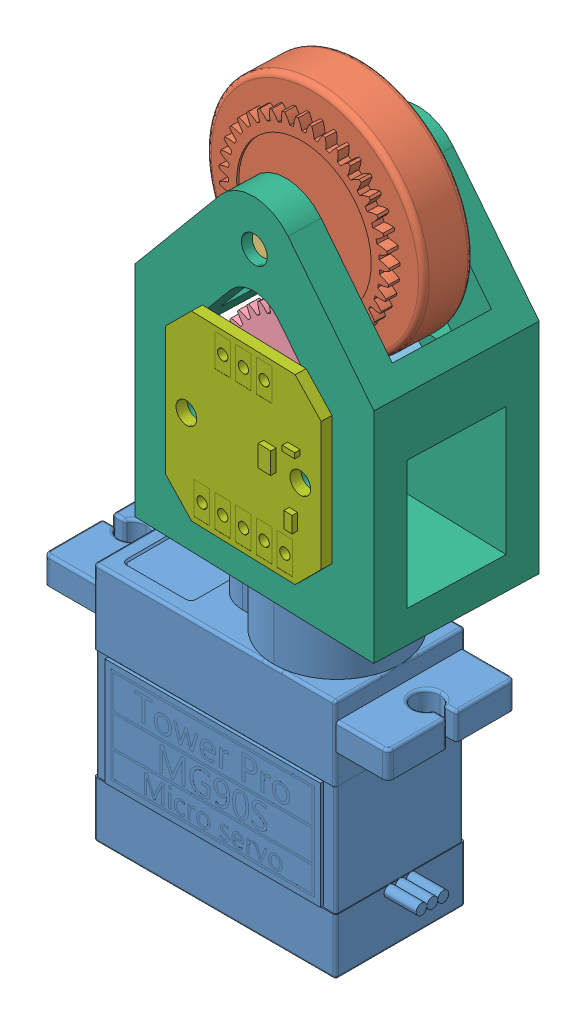
SolidWorks assembly Cum Banh, configuration Default. Lengths in mm.
Overall size (34.77 70 23.37).
9 component instances, 9 part files, 20 mates.
Components (placement in the parent):
- Tower Pro MG90S Micro servo.step-1: Tower Pro MG90S Micro servo.step [Default] at (15.3715 12.0782 26.2271) size (32.2 32.25 12.33)
- Banh xe-1: Banh xe [Default] at (25.5496 58.2792 32.0289) x (0.030859 0 -0.999524) z (-0.29972 -0.953982 -0.009253) size (8.5 21 21)
- Truc 2x14-1: Truc 2x14 [Default] at (20.7542 57.6422 25.9772) x (0.896654 -0.441865 0.027683) z (-0.030859 0 0.999524) size (2 2 14)
- Banh rang doi-1: Banh rang doi [Default] at (20.6271 42.0017 27.2888) x (0.030859 0 -0.999524) z (0.999258 0.023056 0.030851) size (2.5 16.39 16.39)
- Dong co-1: Dong co [Default] at (20.7465 42.0532 26.2271) x (0.999524 0 0.030859) z (0.030859 0 -0.999524) size (10 8 17)
- Ga cum banh-2: Ga cum banh [Default] at (20.5151 57.6422 33.7235) x (0.999524 0 0.030859) z (0.030859 0 -0.999524) size (23.08 31.84 15)
- Encoder-1: Encoder [Default] at (20.4842 42.0532 34.7231) x (0 -1 0) z (0.030859 0 -0.999524) size (17 15 2.5)
- Bao banh xe-1: Bao banh xe [Default] at (20.7074 41.0532 26.2259) x (-0.030859 0 0.999524) z (0.999524 0 0.030859) size (25 22 27) (hidden)
- Nam cham-1: Nam cham [Default] at (20.6539 42.0532 29.2257) x (0.702275 -0.711576 0.021682) z (-0.030859 0 0.999524) size (5 5 1)
Mates (geometry in assembly coordinates):
- Concentric1: concentric aligned: cylinder of Banh xe-1 through (19.1419 57.6422 78.2024) axis (0.030859 0 -0.999524) radius 1; cylinder of Truc 2x14-1 through (20.5382 57.6422 32.9739) axis (0.030859 0 -0.999524) radius 1
- Width1: width anti-aligned: plane of Truc 2x14-1 through (20.5382 57.6422 32.9739) normal (-0.030859 0 0.999524); plane of Truc 2x14-1 through (20.9703 57.6422 18.9806) normal (0.030859 0 -0.999524); plane of Banh xe-1 through (30.9357 54.8314 24.0405) normal (0.030859 0 -0.999524); plane of Banh xe-1 through (30.7968 54.8314 28.5384) normal (-0.030859 0 0.999524)
- Coincident2: coincident aligned: plane of Banh xe-1 through (20.6539 57.6422 29.2257) normal (-0.030859 0 0.999524); plane of Banh rang doi-1 through (20.6539 42.0532 29.2257) normal (-0.030859 0 0.999524)
- Concentric3: concentric anti-aligned: cylinder of Banh rang doi-1 through (22.2278 42.0532 -21.7501) axis (-0.030859 0 0.999524) radius 1; cylinder of Dong co-1 through (20.6539 42.0532 29.2257) axis (0.030859 0 -0.999524) radius 0.5
- Coincident3: coincident aligned: plane of Banh rang doi-1 through (20.6539 42.0532 29.2257) normal (-0.030859 0 0.999524); plane of Dong co-1 through (20.6539 42.0532 29.2257) normal (-0.030859 0 0.999524)
- Concentric4: concentric anti-aligned: cylinder of Truc 2x14-1 through (20.5382 57.6422 32.9739) axis (0.030859 0 -0.999524) radius 1; cylinder of Ga cum banh-2 through (20.6077 57.6422 30.725) axis (-0.030859 0 0.999524) radius 1.25
- Distance2: distance = 0.5 mm anti-aligned: plane of Banh xe-1 through (20.6231 57.6422 30.2252) normal (-0.030859 0 0.999524); plane of Ga cum banh-2 through (20.6077 57.6422 30.725) normal (0.030859 0 -0.999524)
- Concentric12: concentric aligned: cylinder of Dong co-1 through (21.1323 42.0532 13.7331) axis (-0.030859 0 0.999524) radius 5; cylinder of Ga cum banh-2 through (21.3732 42.0532 5.9305) axis (-0.030859 0 0.999524) radius 5
- Concentric13: concentric aligned: cylinder of Tower Pro MG90S Micro servo.step-1 through (20.7465 29.6032 26.2271) axis (0 -1 0) radius 1.7; cylinder of Ga cum banh-2 through (20.7465 34.0532 26.2271) axis (0 -1 0) radius 2.5
- Coincident13: coincident aligned: plane of Tower Pro MG90S Micro servo.step-1 through (20.7465 33.0532 26.2271) normal (0 1 0); plane of Ga cum banh-2 through (8.3913 33.0532 21.3435) normal (0 1 0)
- GearMate1: gear = 14.598 : 14.598 mm: circle of Banh rang doi-1; circle of Banh xe-1
- Concentric14: concentric aligned: cylinder of Ga cum banh-2 through (26.3669 42.0532 22.4135) axis (-0.030859 0 0.999524) radius 1; cylinder of Encoder-1 through (26.0125 42.0532 33.8933) axis (-0.030859 0 0.999524) radius 1
- Concentric15: concentric aligned: cylinder of Ga cum banh-2 through (15.3721 42.0532 22.074) axis (-0.030859 0 0.999524) radius 1; cylinder of Encoder-1 through (15.0177 42.0532 33.5538) axis (-0.030859 0 0.999524) radius 1
- Coincident14: coincident anti-aligned: plane of Ga cum banh-2 through (20.5151 57.6422 33.7235) normal (-0.030859 0 0.999524); plane of Encoder-1 through (20.5151 42.0532 33.7235) normal (0.030859 0 -0.999524)
- Coincident15: coincident anti-aligned: plane of Dong co-1 through (18.1337 46.0532 13.6405) normal (0 1 0); plane of Ga cum banh-2 through (8.8791 46.0532 5.5448) normal (0 -1 0)
- Coincident16: coincident anti-aligned: plane of Ga cum banh-2 through (9.4443 45.0532 18.3746) normal (-0.999524 0 -0.030859); plane of Bao banh xe-1 through (9.5369 30.0532 15.376) normal (0.999524 0 0.030859)
- Width2: width aligned: plane of Ga cum banh-2 through (20.978 57.6422 18.7307) normal (0.030859 0 -0.999524); plane of Ga cum banh-2 through (20.5151 57.6422 33.7235) normal (-0.030859 0 0.999524); plane of Bao banh xe-1 through (8.8888 30.0532 36.366) normal (0.030859 0 -0.999524); plane of Bao banh xe-1 through (9.5369 30.0532 15.376) normal (-0.030859 0 0.999524)
- Coincident17: coincident aligned: plane of Ga cum banh-2 through (10.2937 30.0532 -9.137) normal (0 -1 0); plane of Bao banh xe-1 through (20.7074 30.0532 26.2259) normal (0 -1 0)
- Concentric16: concentric anti-aligned: cylinder of Banh rang doi-1 through (22.1969 42.0532 -20.7506) axis (-0.030859 0 0.999524) radius 1; cylinder of Nam cham-1 through (20.6231 42.0532 30.2252) axis (0.030859 0 -0.999524) radius 2.5
- Coincident18: coincident anti-aligned: plane of Banh rang doi-1 through (20.6539 42.0532 29.2257) normal (-0.030859 0 0.999524); plane of Nam cham-1 through (20.6539 42.0532 29.2257) normal (0.030859 0 -0.999524)
